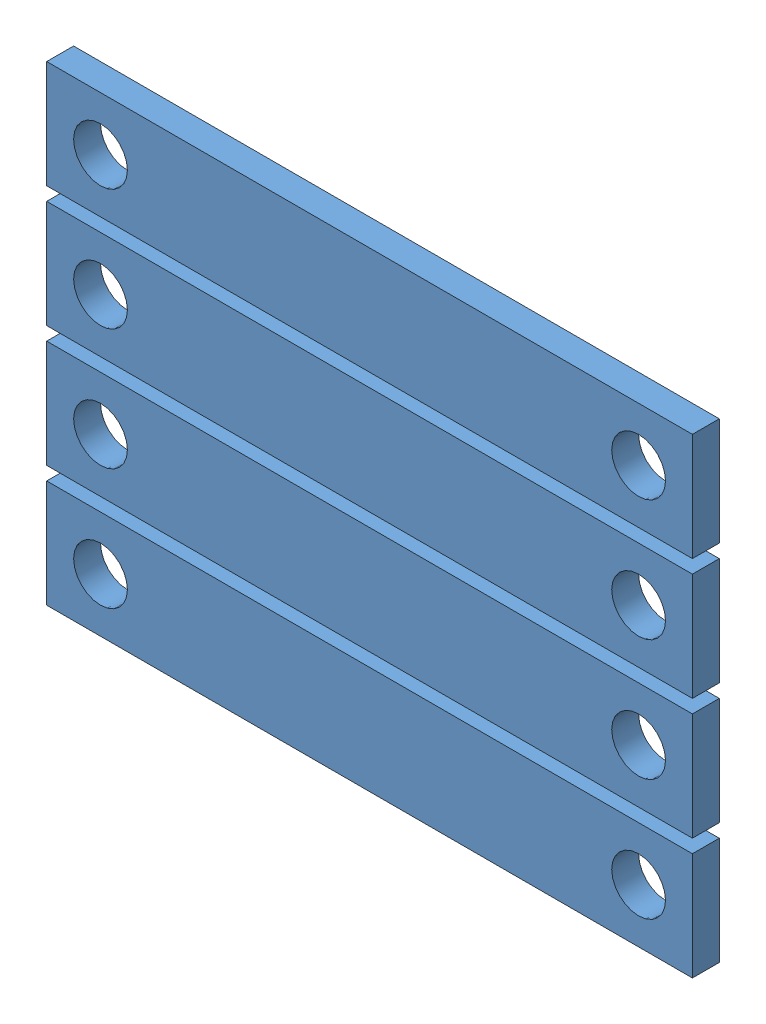
SolidWorks assembly Asm for making plate, configuration Default. Lengths in mm.
Overall size (76.2 55.56 3.17).
4 component instances, 1 part files, 9 mates.
Components (placement in the parent):
- BearingBackPlate-1: BearingBackPlate [Default] at (-6.5558 45.3261 73.1807) size (76.2 12.7 3.17)
- BearingBackPlate-2: BearingBackPlate [Default] at (-6.5558 59.6136 73.1807) size (76.2 12.7 3.17)
- BearingBackPlate-3: BearingBackPlate [Default] at (-6.5558 73.9011 73.1807) size (76.2 12.7 3.17)
- BearingBackPlate-4: BearingBackPlate [Default] at (-6.5558 88.1886 73.1807) size (76.2 12.7 3.17)
Mates (geometry in assembly coordinates):
- Coincident12: coincident aligned: plane of BearingBackPlate-4 through (-6.5558 89.7761 76.3557) normal (0 0 1); plane of BearingBackPlate-3 through (-6.5558 75.4886 76.3557) normal (0 0 1)
- Coincident13: coincident aligned: plane of BearingBackPlate-4 through (-6.5558 89.7761 76.3557) normal (0 0 1); plane of BearingBackPlate-2 through (-6.5558 61.2011 76.3557) normal (0 0 1)
- Coincident14: coincident aligned: plane of BearingBackPlate-4 through (-6.5558 89.7761 76.3557) normal (0 0 1); plane of BearingBackPlate-1 through (-6.5558 45.3261 76.3557) normal (0 0 1)
- Coincident15: coincident aligned: plane of BearingBackPlate-3 through (69.6442 88.1886 76.3557) normal (1 0 0); plane of BearingBackPlate-4 through (69.6442 102.4761 76.3557) normal (1 0 0)
- Coincident16: coincident aligned: plane of BearingBackPlate-2 through (69.6442 73.9011 76.3557) normal (1 0 0); plane of BearingBackPlate-3 through (69.6442 88.1886 76.3557) normal (1 0 0)
- Coincident17: coincident aligned: plane of BearingBackPlate-1 through (69.6442 58.0261 76.3557) normal (1 0 0); plane of BearingBackPlate-2 through (69.6442 73.9011 76.3557) normal (1 0 0)
- Distance3: distance = 1.5875 mm anti-aligned: plane of BearingBackPlate-4 through (69.6442 88.1886 76.3557) normal (0 -1 0); plane of BearingBackPlate-3 through (-6.5558 86.6011 76.3557) normal (0 1 0)
- Distance4: distance = 1.5875 mm anti-aligned: plane of BearingBackPlate-3 through (69.6442 73.9011 76.3557) normal (0 -1 0); plane of BearingBackPlate-2 through (-6.5558 72.3136 76.3557) normal (0 1 0)
- Distance5: distance = 1.5875 mm anti-aligned: plane of BearingBackPlate-2 through (69.6442 59.6136 76.3557) normal (0 -1 0); plane of BearingBackPlate-1 through (-6.5558 58.0261 76.3557) normal (0 1 0)
